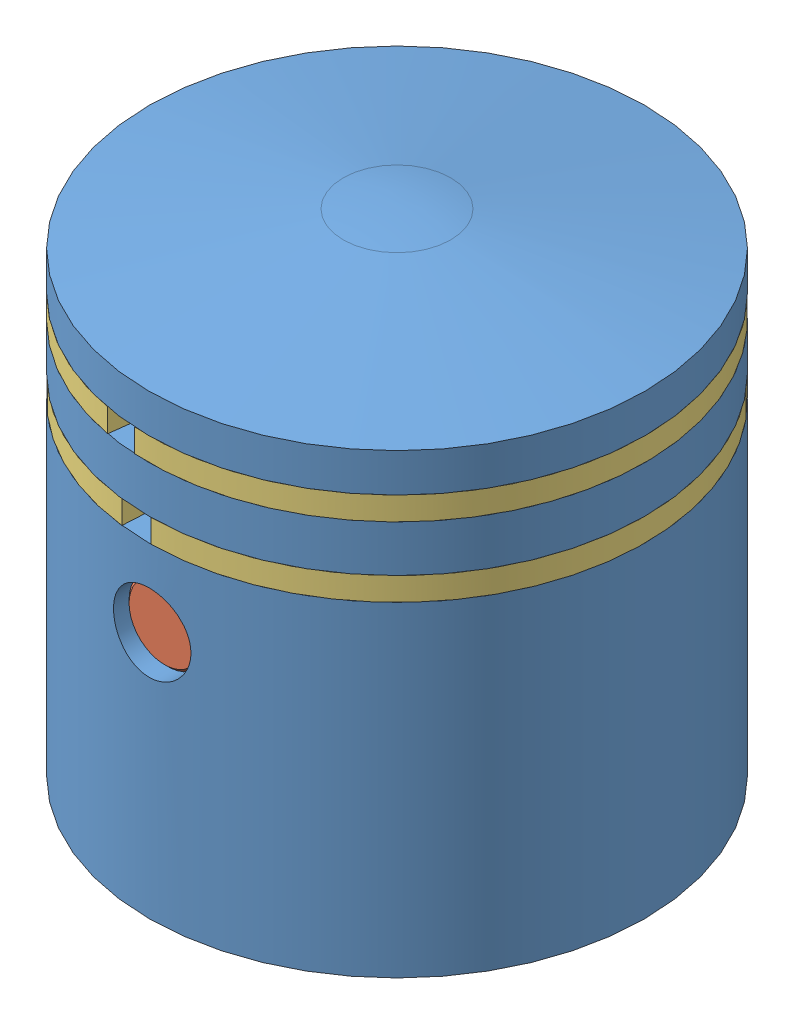
SolidWorks assembly Piston Assembly, configuration Default. Lengths in mm.
Overall size (35.7 32 35.67).
4 component instances, 3 part files, 6 mates.
Components (placement in the parent):
- 4.Piston-1: 4.Piston [Default] at (2.4514 23.7914 24.754) size (32 32 32)
- 5.Piston_Pin-1: 5.Piston_Pin [Default] at (2.4514 23.7914 9.754) size (5 5 30)
- 7.Piston Compression Ring-1: 7.Piston Compression Ring [Default] at (2.4514 34.0414 24.754) x (0.992378 0 0.12323) z (-0.12323 0 0.992378) size (32 1.5 31.97)
- 7.Piston Compression Ring-2: 7.Piston Compression Ring [Default] at (2.4514 29.5414 24.754) x (0.99851 0 0.05457) z (-0.05457 0 0.99851) size (32 1.5 31.97)
Mates (geometry in assembly coordinates):
- Concentric1: concentric: cylinder of 4.Piston-1 through (2.4514 23.7914 8.754) axis (0 0 1) radius 2.5; cylinder of 5.Piston_Pin-1 through (2.4514 23.7914 39.754) axis (0 0 -1) radius 2.5
- Symmetric1: symmetric aligned: plane of 5.Piston_Pin-1 through (2.4514 23.7914 9.754) normal (0 0 -1); plane of 5.Piston_Pin-1 through (2.4514 23.7914 39.754) normal (0 0 1)
- Concentric2: concentric: cylinder of 4.Piston-1 through (2.4514 39.7914 24.754) axis (0 1 0) radius 14.5; cylinder of 7.Piston Compression Ring-1 through (2.4514 34.7914 24.754) axis (0 -1 0) radius 14.5
- Coincident1: coincident anti-aligned: plane of 4.Piston-1 through (18.4514 34.7914 24.754) normal (0 -1 0); plane of 7.Piston Compression Ring-1 through (2.4514 34.7914 24.754) normal (0 1 0)
- Concentric3: concentric: cylinder of 4.Piston-1 through (2.4514 39.7914 24.754) axis (0 1 0) radius 14.5; cylinder of 7.Piston Compression Ring-2 through (2.4514 30.2914 24.754) axis (0 -1 0) radius 14.5
- Coincident2: coincident anti-aligned: plane of 4.Piston-1 through (18.4514 30.2914 24.754) normal (0 -1 0); plane of 7.Piston Compression Ring-2 through (2.4514 30.2914 24.754) normal (0 1 0)
